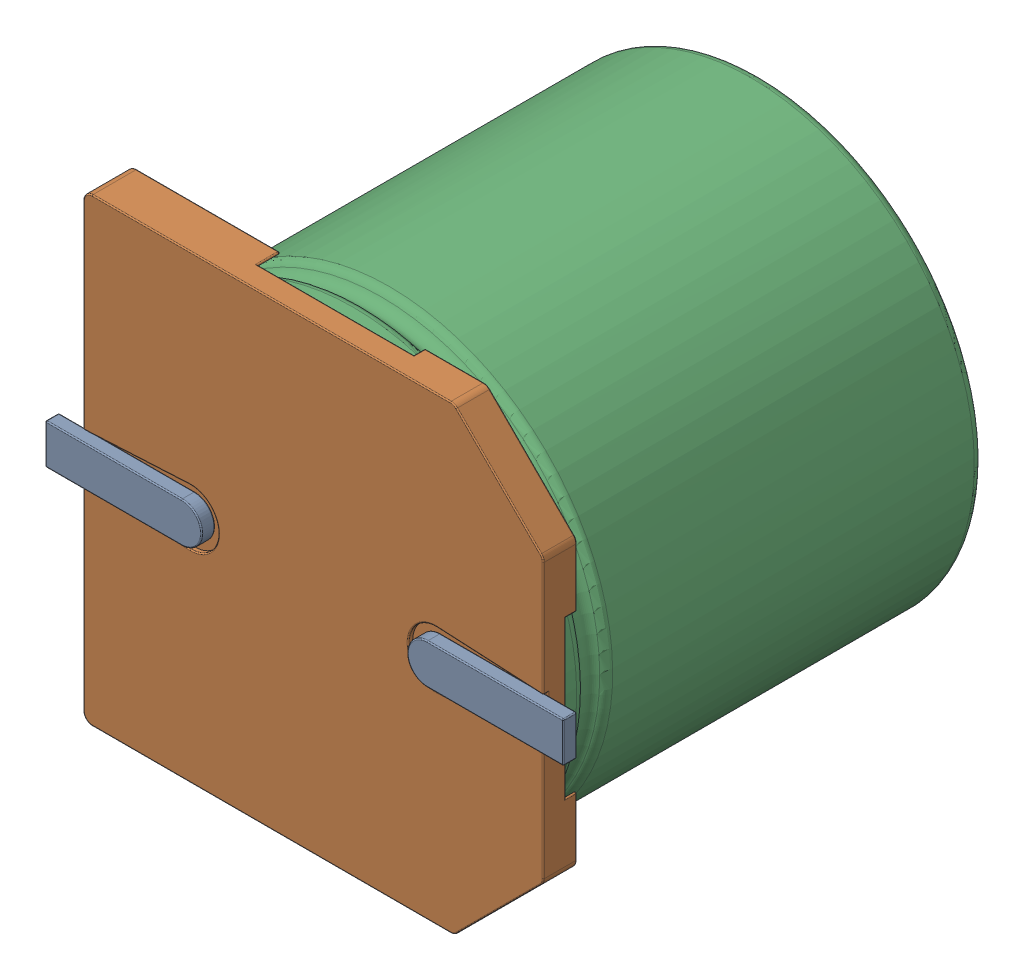
SolidWorks assembly C11, configuration Default. Lengths in mm.
Overall size (11.6 10.3 10.2).
5 component instances, 4 part files, 0 mates.
Components (placement in the parent):
- User_Library-ALU-G-1: User_Library-ALU-G [Default] at (26.6701 5.7149 -1.6914) x (1 0 0) z (0 0 -1) size (11.6 10.3 10.2)
  - Pins_1-1: Pins_1 [Default] at origin size (11.6 0.9 0.35)
  - Fuss_1-1: Fuss_1 [Default] at origin size (10.3 10.3 1)
  - K_X_F6rper_1-1: K_X_F6rper_1 [Default] at origin size (10 10 9.5)
  - Beschriftung_1-1: Beschriftung_1 [Default] at origin size (7.49 8.07 0.06)
